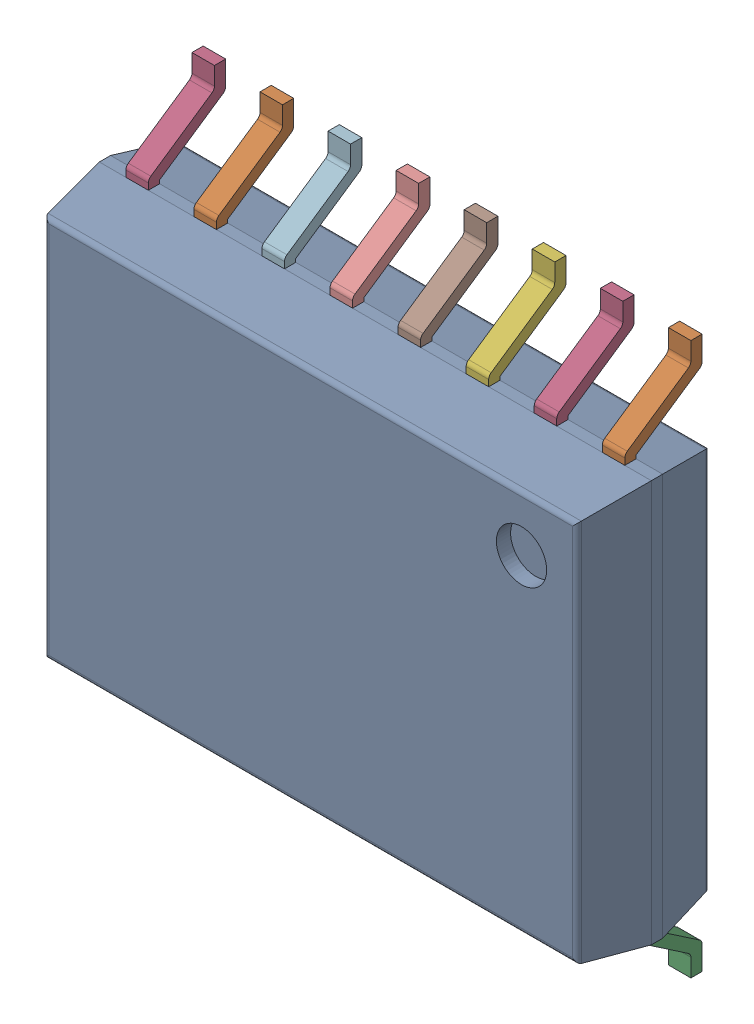
SolidWorks assembly IC2_4.step, configuration Default. Lengths in mm.
Overall size (10.3 10.3 2.65).
3 component instances, 2 part files, 0 mates.
Components (placement in the parent):
- 6383678080.step-1: 6383678080.step [Default] at (125.584 101.326 0) x (0 -1 0) z (0 0 1) size (10.3 10.3 2.65)
  - Body-0_3.step-14: Body-0_3.step [Default] at origin size (7.5 10.3 2.48)
  - PinsArrayLR_4.step-14: PinsArrayLR_4.step [Default] at origin size (10.3 9.31 1.44)
